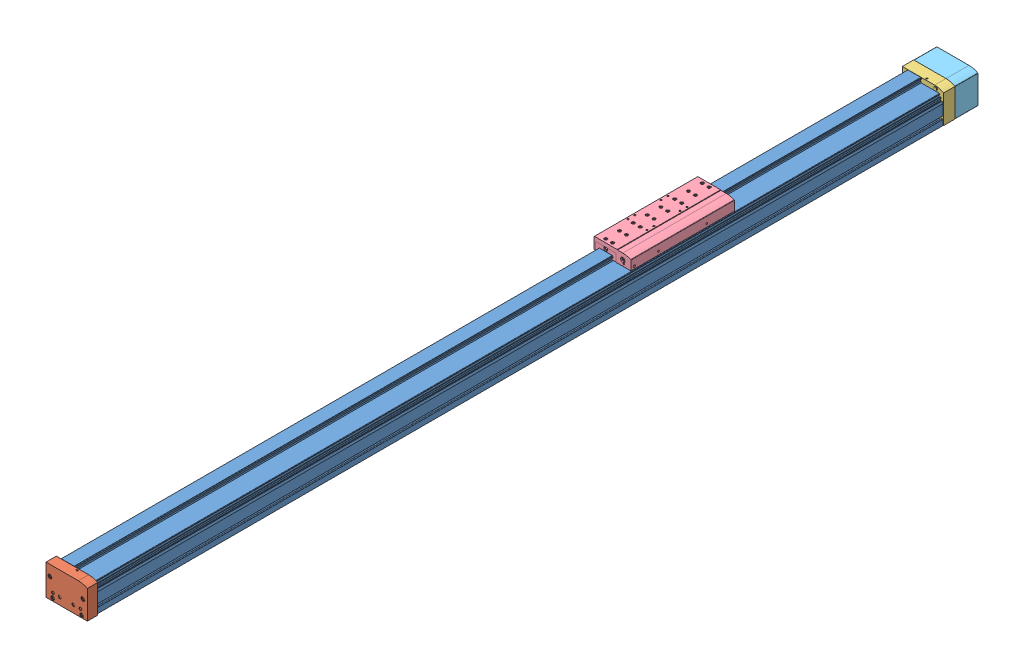
SolidWorks assembly linear_stage, configuration Default. Lengths in mm.
Overall size (122 111.5 2587.5).
5 component instances, 5 part files, 11 mates.
Components (placement in the parent):
- EGC-120-BS2456182GV100--0MR-0_0_R0L22000-1: EGC-120-BS2456182GV100--0MR-0_0_R0L22000 [Default] at (-58 0 1228) size (116 89 2456)
- EGC-120-BS-KF_(Deckel LI1_0)-1: EGC-120-BS-KF_(Deckel LI1_0) [Default] at (62 0 1228) x (-1 0 0) z (0 0 -1) size (120 88.5 32)
- EGC-120-BS-KF_(Deckel RE2_0)-1: EGC-120-BS-KF_(Deckel RE2_0) [Default] at (-60 1 -1228) size (120 88.5 60.5)
- EGC-120-GV-GQBS1----(0)-1: EGC-120-GV-GQBS1----(0) [Default] at (-59 77.5 -332.7186) size (107 34 303.3)
- motor_coupler_housing-1: motor_coupler_housing [Standard] at (18 42.5 -1261) x (-1 0 0) z (0 0 -1) size (120 88.5 70.5)
Mates (geometry in assembly coordinates):
- Concentric1: concentric anti-aligned: cylinder of EGC-120-BS2456182GV100--0MR-0_0_R0L22000-1 through (18 42.5 -1228) axis (0 0 1) radius 25.1; cylinder of EGC-120-BS-KF_(Deckel RE2_0)-1 through (18 42.5 -1226) axis (0 0 -1) radius 25.1
- Coincident1: coincident anti-aligned: plane of EGC-120-BS2456182GV100--0MR-0_0_R0L22000-1 through (-58 0 -1228) normal (0 0 -1); plane of EGC-120-BS-KF_(Deckel RE2_0)-1 through (33.7 32.5 -1228) normal (0 0 1)
- Coincident4: coincident anti-aligned: plane of EGC-120-BS2456182GV100--0MR-0_0_R0L22000-1 through (-4 89 -1228) normal (0 1 0); plane of EGC-120-GV-GQBS1----(0)-1 through (-6.25 89 -312.7186) normal (0 -1 0)
- Parallel4: parallel aligned: plane of EGC-120-BS2456182GV100--0MR-0_0_R0L22000-1 through (-58 68.3 -1228) normal (-1 0 0); plane of EGC-120-BS-KF_(Deckel RE2_0)-1 through (-60 89.5 -1261) normal (-1 0 0)
- Coincident9: coincident anti-aligned: plane of EGC-120-BS2456182GV100--0MR-0_0_R0L22000-1 through (-58 0 1228) normal (0 0 1); plane of EGC-120-BS-KF_(Deckel LI1_0)-1 through (35.7 31.5 1228) normal (0 0 -1)
- Coincident12: coincident aligned: plane of EGC-120-BS2456182GV100--0MR-0_0_R0L22000-1 through (-58 68.3 -1228) normal (-1 0 0); plane of EGC-120-BS-KF_(Deckel LI1_0)-1 through (-58 0 1258) normal (-1 0 0)
- Coincident13: coincident aligned: plane of EGC-120-BS2456182GV100--0MR-0_0_R0L22000-1 through (-58 0 -1228) normal (0 -1 0); plane of EGC-120-BS-KF_(Deckel LI1_0)-1 through (62 0 1258) normal (0 -1 0)
- Coincident14: coincident anti-aligned: plane of EGC-120-BS2456182GV100--0MR-0_0_R0L22000-1 through (-4 75.7 -1228) normal (1 0 0); plane of EGC-120-GV-GQBS1----(0)-1 through (-4 84.74 -312.7186) normal (-1 0 0)
- Coincident15: coincident: plane of EGC-120-BS-KF_(Deckel RE2_0)-1 through (33.7 32.5 -1261) normal (0 0 -1); plane of motor_coupler_housing-1 through (40.5666 95.1163 -1261) normal (0 0 1)
- Concentric2: concentric: cylinder of EGC-120-BS-KF_(Deckel RE2_0)-1 through (18 42.5 -1261) axis (0 0 1) radius 31; cylinder of motor_coupler_housing-1 through (18 42.5 -1329.5) axis (0 0 1) radius 25
- Coincident17: coincident aligned: plane of EGC-120-BS-KF_(Deckel RE2_0)-1 through (60 1 -1261) normal (1 0 0); plane of motor_coupler_housing-1 through (60 82.4591 -1327.5) normal (1 0 0)
